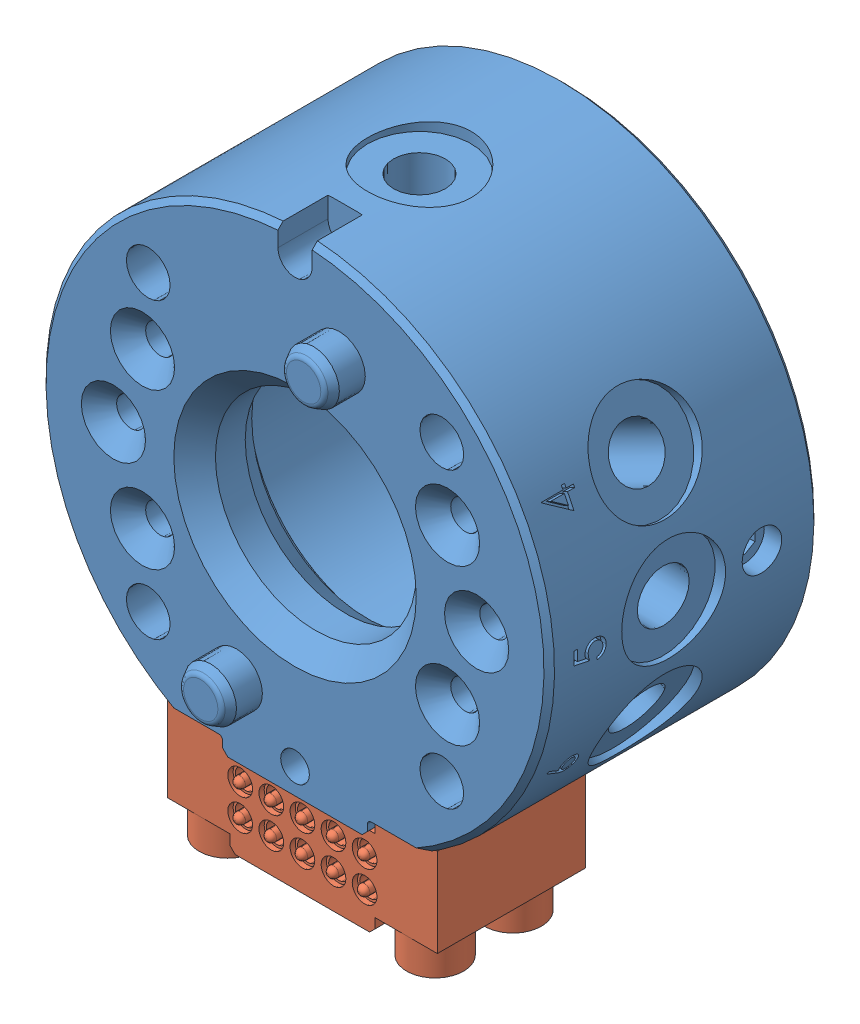
SolidWorks assembly ATI-9120-005T-E10-000, configuration Flat A_E10_. Lengths in mm.
Overall size (49 56.96 29.45).
2 component instances, 2 part files, 3 mates.
Components (placement in the parent):
- ATI-9120-005T-E10-000_QC5-T-1: ATI-9120-005T-E10-000_QC5-T [Default] at origin size (49 46.95 29.45)
- ATI-9120-005T-E10-000_E10T-005-1: ATI-9120-005T-E10-000_E10T-005 [Default] at (-13.0048 -25.9334 -0.7112) x (0 0 1) z (-1 0 0) size (14.76 17 26.01)
Mates (geometry in assembly coordinates):
- Concentric11: concentric aligned: cylinder of ATI-9120-005T-E10-000_QC5-T-1 through (-9.9949 -20.955 -3.5052) axis (0 -1 0) radius 1.25; cylinder of ATI-9120-005T-E10-000_E10T-005-1 through (-9.9949 20.536 -3.5052) axis (0 -1 0) radius 1.5
- Concentric12: concentric aligned: cylinder of ATI-9120-005T-E10-000_QC5-T-1 through (9.9949 -20.955 -10.9982) axis (0 -1 0) radius 1.25; cylinder of ATI-9120-005T-E10-000_E10T-005-1 through (9.9949 20.536 -10.9982) axis (0 -1 0) radius 1.5
- Coincident5: coincident anti-aligned: plane of ATI-9120-005T-E10-000_QC5-T-1 through (-6.9723 -22.4536 -26.0096) normal (0 -1 0); plane of ATI-9120-005T-E10-000_E10T-005-1 through (-7.0104 -22.4536 -7.493) normal (0 1 0)
